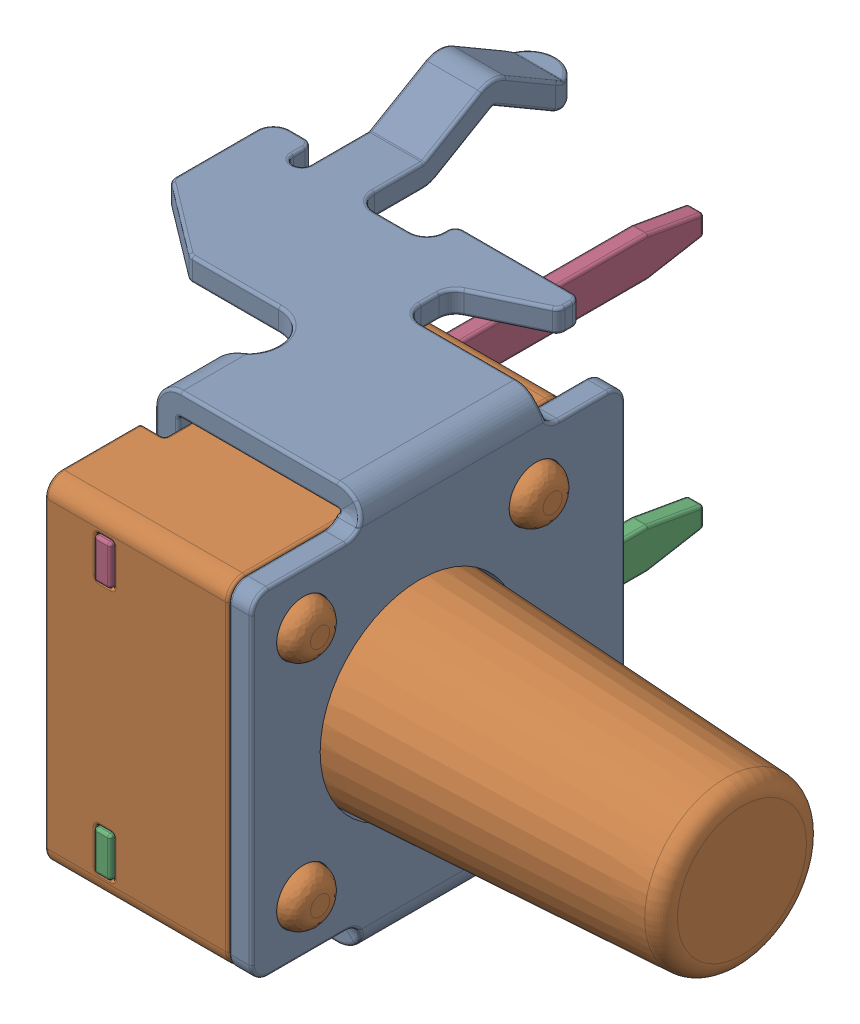
SolidWorks assembly S2, configuration Standard. Lengths in mm.
Overall size (12.35 8.41 10.57).
5 component instances, 4 part files, 0 mates.
Components (placement in the parent):
- S2-subassembly-1-1: S2-subassembly-1 [Standard] at (14.5499 2.4501 0) x (0 1 0) z (0 0 1) size (8.41 12.35 10.57)
  - Tactile Switch SPST-NO Side Actuated Through Hole, Right Angle 1-1825027-1-1: Tactile Switch SPST-NO Side Actuated Through Hole, Right Angle 1-1825027-1 [Standard] at origin size (8.41 6.62 10.52)
  - Tactile Switch SPST-NO Side Actuated Through Hole, Right Angle 1-1825027-1-1-1: Tactile Switch SPST-NO Side Actuated Through Hole, Right Angle 1-1825027-1-1 [Standard] at origin size (5.99 9.42 5.99)
  - Tactile Switch SPST-NO Side Actuated Through Hole, Right Angle 1-1825027-1-2-1: Tactile Switch SPST-NO Side Actuated Through Hole, Right Angle 1-1825027-1-2 [Standard] at origin size (0.71 0.3 10.57)
  - Tactile Switch SPST-NO Side Actuated Through Hole, Right Angle 1-1825027-1-3-1: Tactile Switch SPST-NO Side Actuated Through Hole, Right Angle 1-1825027-1-3 [Standard] at origin size (0.71 0.3 10.57)
